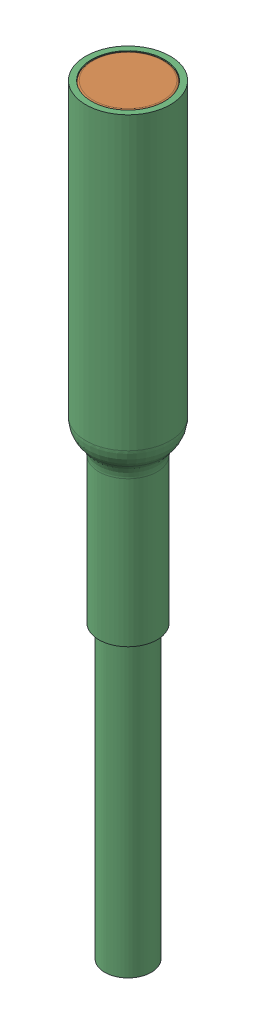
SolidWorks assembly Wire and connection, configuration Default. Lengths in mm.
Overall size (3.68 33.21 3.68).
3 component instances, 3 part files, 4 mates.
Components (placement in the parent):
- Conector-1: Conector [Default] at (665.9041 848.364 1276.0815) size (3.17 9.53 3.17)
- 5862K101_Neodymium Magnet-1: 5862K101_Neodymium Magnet [5862K101] at (665.9041 859.4765 1276.0815) x (1 0 0) z (0 -1 0) size (3.17 3.17 3.17)
- Wire and srink wrap-1: Wire and srink wrap [Default] at (665.9041 827.8508 1276.0815) x (0 1 0) z (0 0 1) size (33.21 3.68 3.68)
Mates (geometry in assembly coordinates):
- Coincident1: coincident anti-aligned: plane of Conector-1 through (665.9041 857.889 1276.0815) normal (0 1 0); plane of 5862K101_Neodymium Magnet-1 through (665.9041 857.889 1276.0815) normal (0 -1 0)
- Concentric1: concentric anti-aligned: cylinder of Conector-1 through (665.9041 857.889 1276.0815) axis (0 -1 0) radius 1.5875; cylinder of 5862K101_Neodymium Magnet-1 through (665.9041 857.889 1276.0815) axis (0 1 0) radius 1.5875
- Coincident2: coincident anti-aligned: plane of Conector-1 through (665.9041 848.364 1276.0815) normal (0 -1 0); plane of Wire and srink wrap-1 through (665.9041 848.364 1275.0655) normal (0 1 0)
- Concentric2: concentric anti-aligned: cylinder of Conector-1 through (665.9041 857.889 1276.0815) axis (0 -1 0) radius 1.5875; cylinder of Wire and srink wrap-1 through (665.9041 853.444 1276.0815) axis (0 1 0) radius 1.8415
